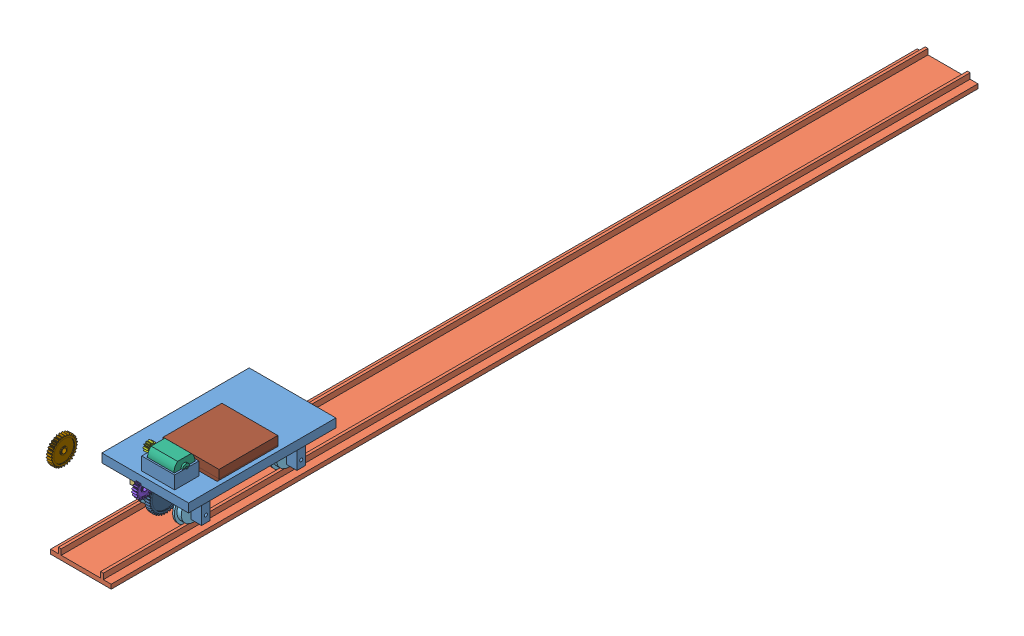
SolidWorks assembly Assem11, configuration Default. Lengths in mm.
Overall size (118.85 93.16 1000).
17 component instances, 12 part files, 36 mates.
Components (placement in the parent):
- Body-1: Body [Default] at (88.2999 57.8 1033.6327) x (-1 0 0) z (0 0 -1) size (100 55 170)
- Rail-1: Rail [Default] at (87.0624 0 691.5866) x (1 0 0) z (0 1 0) size (70 1000 11.5)
- back wheel leg-1: back wheel leg [Default] at (65.2499 47.8 1088.6327) x (-1 0 0) z (0 0 -1) size (28.46 38 39.5)
- front wheel leg-2: front wheel leg [Default] at (65.2499 47.8 978.6327) x (-1 0 0) z (0 0 -1) size (28.46 38 39.5)
- Wheels-1: Wheels [Default] at (66.8824 25.8 978.6327) x (0 0.193783 0.981045) z (-1 0 0) size (34.75 34.75 71.1)
- Wheels-2: Wheels [Default] at (66.8824 25.8 1088.6327) x (0 0.200513 0.979691) z (-1 0 0) size (34.75 34.75 71.1)
- Motor-1: Motor [Default] at (84.0499 72.8 1099.6327) x (0 0 -1) z (1 0 0) size (24.2 18.3 42)
- 10-T-Gear-1: 10-T-Gear [Default] at (77.2999 72.8 1099.6327) x (0 1 0) z (0 0 1) size (10.42 5.5 10.96)
- 20-T-Gear-1: 20-T-Gear [Default] at (83.426 42.4384 1113.596) x (0 -0.48149 -0.876451) z (0 0.876451 -0.48149) size (21.38 5.5 21.38)
- 30-T-Gear-1: 30-T-Gear [Default] at (19.4487 68.1097 1148.6256) x (0 -0.596285 0.802773) z (0 0.802773 0.596285) size (31.14 5.5 31.31)
- 40-T-Gear-1: 40-T-Gear [Default] at (77.926 25.8 1088.6327) x (0 -0.817131 0.576452) z (0 0.576452 0.817131) size (41.62 5.5 41.62)
- Battery-Box-half-1: Battery-Box-half [Default] at (68.8499 49.8 1078.4827) x (1 0 0) z (0 1 0) size (64.45 67.85 9.48)
- Battery-Box-half-2: Battery-Box-half [Default] at (68.8499 68.75 1010.6327) x (1 0 0) z (0 -1 0) size (64.45 67.85 9.48)
- Battery-1: Battery [Default] at (78.5749 59.275 1019.3877) size (14.27 14.27 50.34)
- Battery-2: Battery [Default] at (123.5749 59.275 1019.3877) size (14.27 14.27 50.34)
- Battery-3: Battery [Default] at (108.5749 59.275 1019.3877) size (14.27 14.27 50.34)
- Battery-4: Battery [Default] at (93.5749 59.275 1019.3877) x (0.99683 -0.079561 0) z (0 0 1) size (14.27 14.27 50.34)
Mates (geometry in assembly coordinates):
- Coincident1: coincident anti-aligned: plane of Rail-1 through (87.0624 0 691.5866) normal (0 -1 0); plane of assembly through (0 0 0) normal (0 1 0)
- Coincident2: coincident anti-aligned: plane of Body-1 through (65.2499 57.8 1033.6327) normal (-1 0 0); plane of front wheel leg-2 through (65.2499 47.8 978.6327) normal (1 0 0)
- Coincident3: coincident anti-aligned: plane of Body-1 through (65.2499 55.8 998.6327) normal (0 -1 0); plane of front wheel leg-2 through (38.2999 55.8 958.8827) normal (0 1 0)
- Coincident6: coincident anti-aligned: plane of Body-1 through (65.2499 55.8 1068.6327) normal (0 -1 0); plane of back wheel leg-1 through (38.2999 55.8 1068.8827) normal (0 1 0)
- Coincident7: coincident anti-aligned: plane of Body-1 through (65.2499 57.8 1033.6327) normal (-1 0 0); plane of back wheel leg-1 through (65.2499 47.8 1088.6327) normal (1 0 0)
- Concentric1: concentric anti-aligned: cylinder of back wheel leg-1 through (37.544 25.8 1088.6327) axis (1 0 0) radius 1.75; cylinder of Wheels-2 through (122.6124 25.8 1088.6327) axis (-1 0 0) radius 1.485
- Width1: width aligned: plane of Body-1 through (116.3499 17.8 1093.6327) normal (-1 0 0); plane of back wheel leg-1 through (57.7749 17.8 1083.6327) normal (1 0 0); plane of Wheels-2 through (107.2424 25.8 1088.6327) normal (-1 0 0); plane of Wheels-2 through (66.8824 25.8 1088.6327) normal (1 0 0)
- Width2: width anti-aligned: plane of Body-1 through (116.3499 17.8 973.6327) normal (-1 0 0); plane of front wheel leg-2 through (57.7749 17.8 973.6327) normal (1 0 0); plane of Wheels-1 through (66.8824 25.8 978.6327) normal (1 0 0); plane of Wheels-1 through (107.2424 25.8 978.6327) normal (-1 0 0)
- Concentric2: concentric anti-aligned: cylinder of front wheel leg-2 through (37.544 25.8 978.6327) axis (1 0 0) radius 1.75; cylinder of Wheels-1 through (107.2424 25.8 978.6327) axis (-1 0 0) radius 2.74
- Width3: width aligned: plane of Body-1 through (65.2499 51.8 998.6327) normal (0 0 -1); plane of Body-1 through (65.2499 55.8 958.6327) normal (0 0 1); plane of front wheel leg-2 through (38.2999 51.8 958.8827) normal (0 0 -1); plane of front wheel leg-2 through (38.2999 55.8 998.3827) normal (0 0 1)
- Width4: width aligned: plane of Body-1 through (65.2499 55.8 1108.6327) normal (0 0 -1); plane of Body-1 through (65.2499 51.8 1068.6327) normal (0 0 1); plane of back wheel leg-1 through (38.2999 51.8 1068.8827) normal (0 0 -1); plane of back wheel leg-1 through (38.2999 55.8 1108.3827) normal (0 0 1)
- Parallel1: parallel aligned: plane of Body-1 through (88.2999 57.8 1033.6327) normal (0 1 0); plane of assembly through (0 0 0) normal (0 1 0)
- Parallel3: parallel anti-aligned: plane of Body-1 through (38.2999 47.8 948.6327) normal (0 0 -1); plane of assembly through (0 0 0) normal (0 0 1)
- Tangent2: tangent anti-aligned: plane of Rail-1 through (87.0624 11.5 691.5866) normal (0 1 0); cylinder of Wheels-1 through (114.1124 25.8 978.6327) axis (-1 0 0) radius 14.3
- Width5: width anti-aligned: plane of Wheels-1 through (114.1124 25.8 978.6327) normal (1 0 0); plane of Wheels-1 through (60.0124 25.8 978.6327) normal (-1 0 0); plane of Rail-1 through (61.1574 11.5 1191.5866) normal (-1 0 0); plane of Rail-1 through (112.9674 11.5 191.5866) normal (1 0 0)
- Concentric3: concentric aligned: cylinder of Body-1 through (38.2999 72.8 1099.6327) axis (1 0 0) radius 1.5; cylinder of Motor-1 through (75.5999 72.8 1099.6327) axis (1 0 0) radius 1
- Width6: width aligned: plane of Body-1 through (115.2999 72.8 1099.6327) normal (-1 0 0); plane of Body-1 through (83.2999 72.8 1099.6327) normal (1 0 0); plane of Motor-1 through (84.0499 72.8 1099.6327) normal (-1 0 0); plane of Motor-1 through (114.5499 72.8 1099.6327) normal (1 0 0)
- Parallel4: parallel aligned: plane of Body-1 through (88.2999 72.8 1033.6327) normal (0 1 0); plane of Motor-1 through (114.5499 81.95 1107.5502) normal (0 1 0)
- Concentric4: concentric anti-aligned: cylinder of Motor-1 through (75.5999 72.8 1099.6327) axis (1 0 0) radius 1; cylinder of 10-T-Gear-1 through (77.2999 72.8 1099.6327) axis (-1 0 0) radius 1.5
- Distance1: distance = 2 mm anti-aligned: plane of 10-T-Gear-1 through (77.2999 73.8392 1095.5891) normal (1 0 0); plane of Body-1 through (79.2999 72.8 1113.6327) normal (-1 0 0)
- Coincident13: coincident anti-aligned: plane of Body-1 through (88.2999 49.8 1033.6327) normal (0 1 0); plane of Battery-Box-half-1 through (68.8499 49.8 1078.4827) normal (0 -1 0)
- Coincident14: coincident anti-aligned: plane of Body-1 through (133.2999 49.8 1010.6327) normal (0 0 1); plane of Battery-Box-half-1 through (68.8499 68.75 1010.6327) normal (0 0 -1)
- Coincident15: coincident anti-aligned: plane of Body-1 through (133.2999 49.8 1010.6327) normal (-1 0 0); plane of Battery-Box-half-1 through (133.2999 68.75 1078.4827) normal (1 0 0)
- Concentric12: concentric anti-aligned: cylinder of Wheels-2 through (107.2424 25.8 1088.6327) axis (-1 0 0) radius 2.74; cylinder of 40-T-Gear-1 through (77.926 25.8 1088.6327) axis (1 0 0) radius 2.75
- Tangent8: tangent: circle of 20-T-Gear-1; circle of 40-T-Gear-1
- Concentric16: concentric anti-aligned: cylinder of Battery-Box-half-1 through (78.5749 59.275 1019.3877) axis (0 0 1) radius 7.135; cylinder of Battery-1 through (78.5749 59.275 1069.7277) axis (0 0 -1) radius 7.135
- Coincident16: coincident anti-aligned: plane of Battery-Box-half-1 through (78.5749 59.275 1069.7277) normal (0 0 -1); plane of Battery-1 through (78.5749 59.275 1069.7277) normal (0 0 1)
- Concentric17: concentric anti-aligned: cylinder of Battery-Box-half-1 through (93.5749 59.275 1019.3877) axis (0 0 1) radius 7.135; cylinder of Battery-4 through (93.5749 59.275 1069.7277) axis (0 0 -1) radius 7.135
- Coincident17: coincident anti-aligned: plane of Battery-Box-half-1 through (93.5749 59.275 1069.7277) normal (0 0 -1); plane of Battery-4 through (93.5749 59.275 1069.7277) normal (0 0 1)
- Concentric18: concentric anti-aligned: cylinder of Battery-Box-half-1 through (108.5749 59.275 1019.3877) axis (0 0 1) radius 7.135; cylinder of Battery-3 through (108.5749 59.275 1069.7277) axis (0 0 -1) radius 7.135
- Coincident18: coincident anti-aligned: plane of Battery-Box-half-1 through (108.5749 59.275 1069.7277) normal (0 0 -1); plane of Battery-3 through (108.5749 59.275 1069.7277) normal (0 0 1)
- Concentric19: concentric anti-aligned: cylinder of Battery-Box-half-1 through (123.5749 59.275 1019.3877) axis (0 0 1) radius 7.135; cylinder of Battery-2 through (123.5749 59.275 1069.7277) axis (0 0 -1) radius 7.135
- Coincident19: coincident anti-aligned: plane of Battery-Box-half-1 through (123.5749 59.275 1069.7277) normal (0 0 -1); plane of Battery-2 through (123.5749 59.275 1069.7277) normal (0 0 1)
- Coincident20: coincident anti-aligned: plane of Battery-Box-half-1 through (68.8499 59.275 1010.6327) normal (0 1 0); plane of Battery-Box-half-2 through (68.8499 59.275 1078.4827) normal (0 -1 0)
- Coincident21: coincident aligned: plane of Battery-Box-half-1 through (68.8499 68.75 1078.4827) normal (-1 0 0); plane of Battery-Box-half-2 through (68.8499 49.8 1010.6327) normal (-1 0 0)
- Coincident22: coincident aligned: plane of Battery-Box-half-1 through (68.8499 68.75 1078.4827) normal (0 0 1); plane of Battery-Box-half-2 through (68.8499 49.8 1078.4827) normal (0 0 1)
